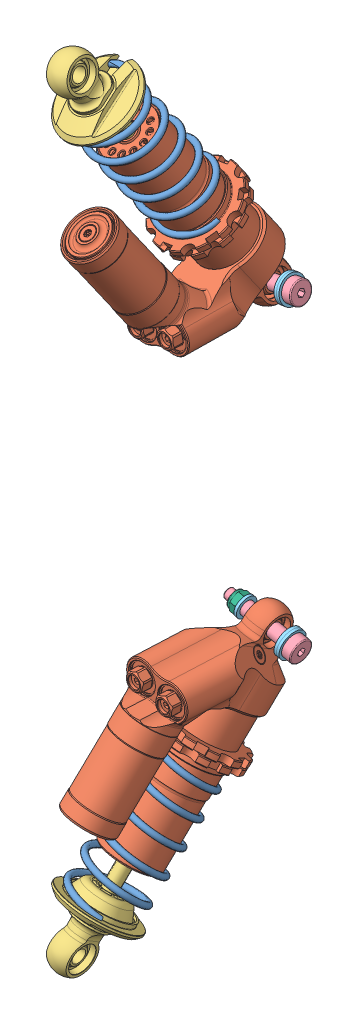
SolidWorks assembly PUTM-S-SR-DS-Dampers, configuration Domyślna. Lengths in mm.
Overall size (85.35 513.33 145.32).
16 component instances, 6 part files, 11 mates.
Components (placement in the parent):
- PUTM-S-SF-DS-Spring-1: PUTM-S-SF-DS-Spring [Domyślna] at (-1444.1735 -212.7911 512.9654) x (0.986637 -0.144478 0.075328) z (0.014827 0.540008 0.841529) size (39.96 93.9 39.96)
- PUTM-S-SF-DS-Ohlines TTX25-Body-2: PUTM-S-SF-DS-Ohlines TTX25-Body [Default] at (-1439.9074 190.9912 498.9013) x (-0.983754 -0.17813 -0.022291) z (0.076805 -0.529861 0.8446) size (49.5 133.26 84.25)
- PUTM-S-SF-DS-Ohlines TTX25-Head-2: PUTM-S-SF-DS-Ohlines TTX25-Head [Default] at (-1435.0737 166.2906 482.9658) x (-0.98031 -0.197286 0.008446) z (0.112538 -0.52303 0.844852) size (46 110.31 45.56)
- PUTM-S-SF-DS-Spring-2: PUTM-S-SF-DS-Spring [Domyślna] at (-1430.6617 143.7448 468.4204) x (0.771486 0.444597 -0.455129) z (0.615208 -0.338845 0.711831) size (39.96 93.9 39.96)
- PUTM-S-SF-DS-Ohlines TTX25-Body-4: PUTM-S-SF-DS-Ohlines TTX25-Body [Default] at (-1439.9074 -190.9912 498.9013) x (0.984775 -0.170339 0.034677) z (0.062367 0.532416 0.844182) size (49.5 133.26 84.25)
- PUTM-S-SF-DS-Ohlines TTX25-Head-4: PUTM-S-SF-DS-Ohlines TTX25-Head [Default] at (-1435.0737 -166.2906 482.9658) x (0.984775 -0.170339 0.034677) z (0.062367 0.532416 0.844182) size (46 110.31 45.56)
- PUTM-FT-ELESA_ISO7379-1: PUTM-FT-ELESA_ISO7379 [8-M6-30] at (-1399.0076 94.942 434.9254) x (0.983754 0.17813 0.022291) z (-0.160533 0.928479 -0.334898) size (46.5 13 13)
- PUTM-FT-FABORY_ISO7089-1: PUTM-FT-FABORY_ISO7089 [M6 [38093.060.001]] at (-1434.7179 88.4759 434.1163) x (0.07174 -0.276262 -0.958401) z (0.983754 0.17813 0.022291) size (12 12 1.6)
- PUTM-FT-FABORY_DIN985-1: PUTM-FT-FABORY_DIN985 [M6 [12348.060.001]] at (-1434.7179 88.4759 434.1163) x (0.128383 -0.611294 -0.780921) z (-0.983754 -0.17813 -0.022291) size (11.9 10.35 6.18)
- PUTM-FT-FABORY_ISO7089-2: PUTM-FT-FABORY_ISO7089 [M8 [38093.080.001]] at (-1405.9923 93.6773 434.7672) x (0.05333 -0.171415 -0.983754) z (0.983754 0.17813 0.022291) size (16 16 1.6)
- PUTM-FT-FABORY_ISO7089-3: PUTM-FT-FABORY_ISO7089 [M8 [38093.080.001]] at (-1407.5663 93.3923 434.7315) x (0.05333 -0.171415 -0.983754) z (0.983754 0.17813 0.022291) size (16 16 1.6)
- PUTM-FT-ELESA_ISO7379-2: PUTM-FT-ELESA_ISO7379 [8-M6-30] at (-1399.0076 -94.942 434.9254) x (0.983754 -0.17813 0.022291) z (0.160533 0.928479 0.334898) size (46.5 13 13)
- PUTM-FT-FABORY_DIN985-2: PUTM-FT-FABORY_DIN985 [M6 [12348.060.001]] at (-1434.7179 -88.4759 434.1163) x (-0.128383 -0.611294 0.780921) z (-0.983754 0.17813 -0.022291) size (11.9 10.35 6.18)
- PUTM-FT-FABORY_ISO7089-4: PUTM-FT-FABORY_ISO7089 [M6 [38093.060.001]] at (-1433.1439 -88.7609 434.1519) x (0.07174 0.276262 -0.958401) z (-0.983754 0.17813 -0.022291) size (12 12 1.6)
- PUTM-FT-FABORY_ISO7089-5: PUTM-FT-FABORY_ISO7089 [M8 [38093.080.001]] at (-1404.4183 -93.9623 434.8028) x (0.05333 0.171415 -0.983754) z (-0.983754 0.17813 -0.022291) size (16 16 1.6)
- PUTM-FT-FABORY_ISO7089-6: PUTM-FT-FABORY_ISO7089 [M8 [38093.080.001]] at (-1405.9923 -93.6773 434.7672) x (0.05333 0.171415 -0.983754) z (-0.983754 0.17813 -0.022291) size (16 16 1.6)
Mates (geometry in assembly coordinates):
- Koncentryczne13: concentric aligned: cone of PUTM-S-SF-DS-Ohlines TTX25-Body-2 through (-1439.8547 190.7217 498.7274) axis (-0.16226 0.829167 0.534934); cylinder of PUTM-S-SF-DS-Ohlines TTX25-Head-2 through (-1446.2697 223.5031 519.8762) axis (-0.16226 0.829167 0.534934) radius 3.9935
- Koncentryczne14: concentric aligned: line of PUTM-S-SF-DS-Spring-1 through (-1428.7435 -133.9422 462.0963) axis (-0.16226 -0.829167 0.534934); cylinder of PUTM-S-SF-DS-Ohlines TTX25-Body-4 through (-1439.9074 -190.9912 498.9013) axis (-0.16226 -0.829167 0.534934) radius 16.3
- Koncentryczne18: concentric aligned: cylinder of PUTM-S-SF-DS-Ohlines TTX25-Body-4 through (-1439.9074 -190.9912 498.9013) axis (-0.16226 -0.829167 0.534934) radius 16.95; cylinder of PUTM-S-SF-DS-Ohlines TTX25-Head-4 through (-1446.2697 -223.5031 519.8762) axis (-0.16226 -0.829167 0.534934) radius 3.9935
- Koncentryczne19: concentric anti-aligned: cylinder of PUTM-S-SF-DS-Ohlines TTX25-Body-2 through (-1409.3427 93.0706 434.6913) axis (0.983754 0.17813 0.022291) radius 4; cylinder of PUTM-FT-ELESA_ISO7379-1 through (-1399.0076 94.942 434.9254) axis (-0.983754 -0.17813 -0.022291) radius 4
- Koncentryczne20: concentric aligned: cylinder of PUTM-FT-ELESA_ISO7379-1 through (-1399.0076 94.942 434.9254) axis (-0.983754 -0.17813 -0.022291) radius 3; cylinder of PUTM-FT-FABORY_ISO7089-1 through (-1433.1439 88.7609 434.1519) axis (-0.983754 -0.17813 -0.022291) radius 3.2
- Koncentryczne21: concentric anti-aligned: cylinder of PUTM-FT-ELESA_ISO7379-1 through (-1399.0076 94.942 434.9254) axis (-0.983754 -0.17813 -0.022291) radius 3; cylinder of PUTM-FT-FABORY_DIN985-1 through (-1438.6529 87.7634 434.0271) axis (0.983754 0.17813 0.022291) radius 3
- Wspólnie1: coincident anti-aligned: plane of PUTM-FT-FABORY_ISO7089-1 through (-1434.7179 88.4759 434.1163) normal (-0.983754 -0.17813 -0.022291); plane of PUTM-FT-FABORY_DIN985-1 through (-1434.7179 88.4759 434.1163) normal (0.983754 0.17813 0.022291)
- Koncentryczne22: concentric aligned: cylinder of PUTM-FT-ELESA_ISO7379-1 through (-1399.0076 94.942 434.9254) axis (-0.983754 -0.17813 -0.022291) radius 4; cylinder of PUTM-FT-FABORY_ISO7089-2 through (-1404.4183 93.9623 434.8028) axis (-0.983754 -0.17813 -0.022291) radius 4.2
- Wspólnie6: coincident anti-aligned: plane of PUTM-FT-ELESA_ISO7379-1 through (-1403.896 91.8441 428.6799) normal (-0.983754 -0.17813 -0.022291); plane of PUTM-FT-FABORY_ISO7089-2 through (-1404.4183 93.9623 434.8028) normal (0.983754 0.17813 0.022291)
- Koncentryczne23: concentric aligned: cylinder of PUTM-FT-ELESA_ISO7379-1 through (-1399.0076 94.942 434.9254) axis (-0.983754 -0.17813 -0.022291) radius 4; cylinder of PUTM-FT-FABORY_ISO7089-3 through (-1405.9923 93.6773 434.7672) axis (-0.983754 -0.17813 -0.022291) radius 4.2
- Wspólnie7: coincident anti-aligned: plane of PUTM-FT-FABORY_ISO7089-2 through (-1405.9923 93.6773 434.7672) normal (-0.983754 -0.17813 -0.022291); plane of PUTM-FT-FABORY_ISO7089-3 through (-1405.9923 93.6773 434.7672) normal (0.983754 0.17813 0.022291)
